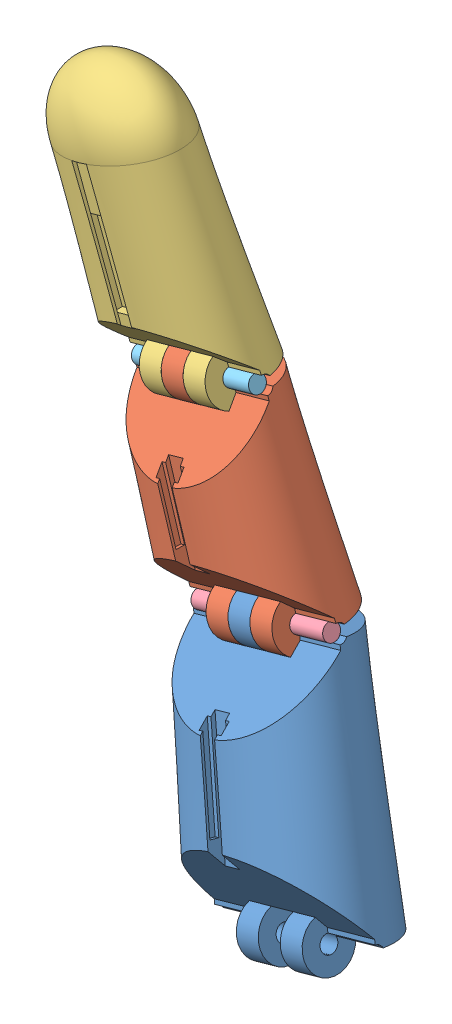
SolidWorks assembly Assem1 index and ring, configuration Default. Lengths in mm.
Overall size (46.69 90.74 23.77).
5 component instances, 5 part files, 8 mates.
Components (placement in the parent):
- part 1 ind-1: part 1 ind [Default] at (-17.4645 65.0369 -4.3815) x (-0.950377 -0.306201 -0.054985) z (-0.102598 0.141635 0.984588) size (22.08 35 17.01)
- part 2 ind-1: part 2 ind [Default] at (-24.8544 87.8504 -3.6973) x (-0.950377 -0.306201 -0.054985) z (-0.042281 -0.047975 0.997953) size (20.07 30 15.01)
- part 3 ind-1: part 3 ind [Default] at (-32.2884 110.5966 -1.8742) x (-0.950377 -0.306201 -0.054985) z (-0.028567 -0.090104 0.995523) size (18.07 34.5 13.01)
- mate1-1: mate1 [Default] at (-26.1648 62.7518 -4.9594) x (0.143858 -0.27584 -0.950377) z (0.950377 0.306201 0.054985) size (2 2 18)
- mate2-1: mate2 [Default] at (-32.6115 85.8762 -4.1209) x (0.143858 -0.27584 -0.950377) z (0.950377 0.306201 0.054985) size (2 2 16)
Mates (geometry in assembly coordinates):
- Concentric1: concentric aligned: cylinder of part 1 ind-1 through (-7.1466 68.8793 -3.8591) axis (-0.950377 -0.306201 -0.054985) radius 1; cylinder of part 2 ind-1 through (-8.0975 68.5729 -3.9141) axis (-0.950377 -0.306201 -0.054985) radius 1
- Coincident1: coincident anti-aligned: plane of part 1 ind-1 through (-16.1858 65.9669 -4.382) normal (0.950377 0.306201 0.054985); plane of part 2 ind-1 through (-16.1858 65.9669 -4.382) normal (-0.950377 -0.306201 -0.054985)
- Concentric2: concentric anti-aligned: cylinder of part 2 ind-1 through (-15.4946 91.3911 -3.1305) axis (-0.950377 -0.306201 -0.054985) radius 1; cylinder of part 3 ind-1 through (-33.571 85.567 -4.1764) axis (0.950377 0.306201 0.054985) radius 1
- Coincident2: coincident anti-aligned: plane of part 2 ind-1 through (-23.5829 88.7851 -3.5985) normal (0.950377 0.306201 0.054985); plane of part 3 ind-1 through (-23.5829 88.7851 -3.5985) normal (-0.950377 -0.306201 -0.054985)
- Concentric3: concentric aligned: cylinder of part 2 ind-1 through (-8.0975 68.5729 -3.9141) axis (-0.950377 -0.306201 -0.054985) radius 1; cylinder of mate1-1 through (-9.058 68.2634 -3.9696) axis (-0.950377 -0.306201 -0.054985) radius 1
- Width1: width aligned: plane of mate1-1 through (-9.058 68.2634 -3.9696) normal (0.950377 0.306201 0.054985); plane of part 2 ind-1 through (-26.1648 62.7518 -4.9594) normal (-0.950377 -0.306201 -0.054985); plane of mate1-1 through (-13.3347 66.8855 -4.2171) normal (0.950377 0.306201 0.054985); plane of part 2 ind-1 through (-21.8881 64.1297 -4.7119) normal (-0.950377 -0.306201 -0.054985)
- Concentric4: concentric anti-aligned: cylinder of part 3 ind-1 through (-33.571 85.567 -4.1764) axis (0.950377 0.306201 0.054985) radius 1; cylinder of mate2-1 through (-17.4055 90.7754 -3.2411) axis (-0.950377 -0.306201 -0.054985) radius 1
- Width2: width anti-aligned: plane of mate2-1 through (-32.6115 85.8762 -4.1209) normal (-0.950377 -0.306201 -0.054985); plane of part 3 ind-1 through (-17.4055 90.7754 -3.2411) normal (0.950377 0.306201 0.054985); plane of mate2-1 through (-20.7318 89.7037 -3.4335) normal (0.950377 0.306201 0.054985); plane of part 3 ind-1 through (-29.2852 86.9479 -3.9284) normal (-0.950377 -0.306201 -0.054985)
